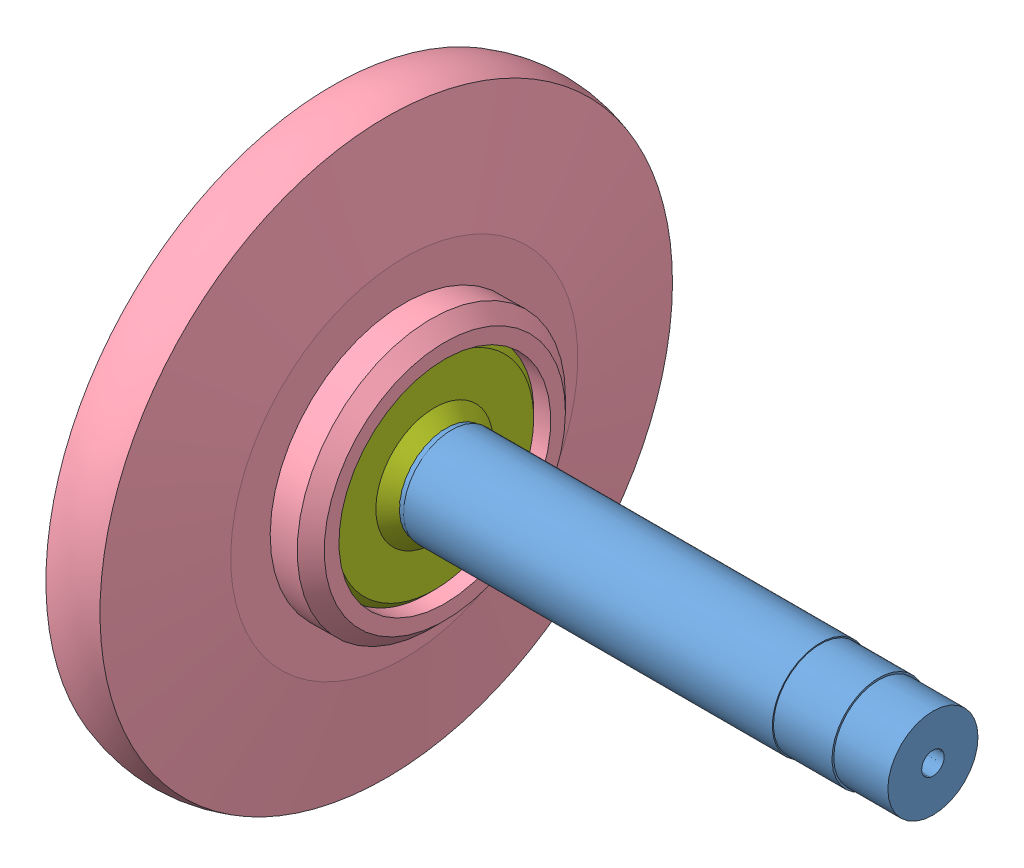
SolidWorks assembly Ось мод(02), configuration 00. Lengths in mm.
Overall size (143.28 136.17 136.17).
8 component instances, 7 part files, 8 mates.
Components (placement in the parent):
- Ось цельная 21_3мм-1: Ось цельная 21_3мм [--] at origin size (131.76 21.3 21.3)
- Шайба оси-1: Шайба оси [--] at (-65.401 0 0) size (4 24 24)
- Болты с шестигранной головкой кт.В (ГОСТ 7798-70)-1: Болты с шестигранной головкой кт.В (ГОСТ 7798-70) [Болт М6-6gx20(S10) ГОСТ 7798-77] at (-68.3812 0 0) x (1 0 0) z (0 -0.163036 0.98662) size (24 10.9 10)
- Каток 129(47) в сборе-1: Каток 129(47) в сборе [00] at (-61.401 0 0) x (-1 0 0) z (0 0.057246 -0.99836) size (35.7 129 129)
  - Каток 129(47)-1: Каток 129(47) [--] at origin size (35 129 129)
  - Подшипник ГОСТ 8338-75 -1: Подшипник ГОСТ 8338-75  [Подшипник 204 ГОСТ 8338-75] at (-1 0 0) x (1 0 0) z (0 -0.327433 -0.944874) size (14 47 47)
  - Стопор внутренний до 165мм (ГОСТ 13943-86)-1: Стопор внутренний до 165мм (ГОСТ 13943-86) [Кольцо 47] at (-8 0 0) x (0 0.910839 0.412761) z (-1 0 0) size (49.5 51.2 1.7)
  - Сальник 47х20-1: Сальник 47х20 [--] at (-9.7 0 0) x (-1 0 0) z (0 0.937697 -0.347453) size (10 47 47)
Mates (geometry in assembly coordinates):
- Совпадение1: coordinate: point of Ось цельная 21_3мм-1; point of assembly
- Совпадение2: coincident: plane of Шайба оси-1 through (-65.401 0 0) normal (0 0 1); plane of assembly through (0 0 0) normal (0 0 1)
- Совпадение3: coincident: plane of Шайба оси-1 through (-65.401 0 0) normal (0 1 0); plane of assembly through (0 0 0) normal (0 1 0)
- Совпадение4: coincident: plane of Ось цельная 21_3мм-1 through (-65.8812 0 0) normal (-1 0 0); plane of Шайба оси-1 through (-65.401 0 0) normal (1 0 0)
- Концентричный1: concentric: cylinder of Шайба оси-1 through (-69.8812 0 0) axis (-1 0 0) radius 3.25; cylinder of Болты с шестигранной головкой кт.В (ГОСТ 7798-70)-1 through (-1068.3812 0 0) axis (-1 0 0) radius 3
- Совпадение5: coincident: plane of Шайба оси-1 through (-68.3812 8.5 0) normal (-1 0 0); plane of Болты с шестигранной головкой кт.В (ГОСТ 7798-70)-1 through (-68.3812 5.3771 0.8885) normal (1 0 0)
- Совпадение6: coincident: plane of Ось цельная 21_3мм-1 through (-53.8812 10.4 0) normal (-1 0 0); plane of Каток 129(47) в сборе-1/Подшипник ГОСТ 8338-75 -1 through (-53.401 -10.6327 -4.3813) normal (1 0 0)
- Концентричный2: concentric: cylinder of Ось цельная 21_3мм-1 through (-65.8812 0 0) axis (-1 0 0) radius 10.4; cylinder of Каток 129(47) в сборе-1/Подшипник ГОСТ 8338-75 -1 through (939.599 0 0) axis (1 0 0) radius 10
